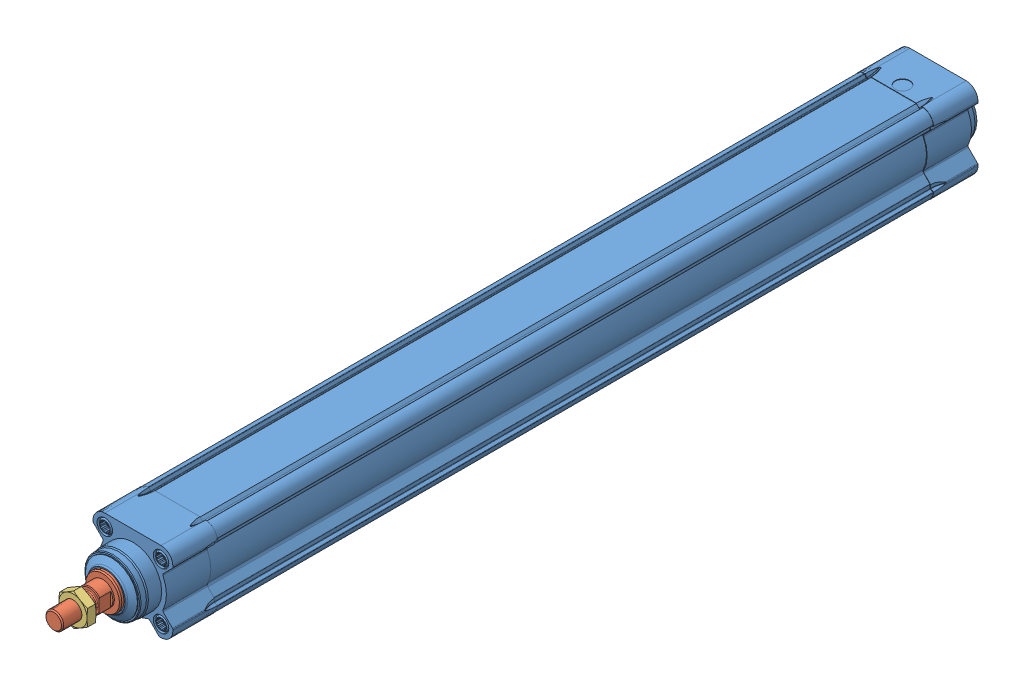
SolidWorks assembly Assem1, configuration Default. Lengths in mm.
Overall size (54 54 615.9).
5 component instances, 5 part files, 12 mates.
Components (placement in the parent):
- ESBF-BS-40-400---(ZR_-_-)-1: ESBF-BS-40-400---(ZR_-_-) [Default] at origin size (54 54 569)
- ESBF-BS-40-400-5P---(KS_0)-1: ESBF-BS-40-400-5P---(KS_0) [Default] at origin size (40 40 567.5)
- DIN-439-B - M12x1_25(F)-1: DIN-439-B - M12x1_25(F) [Default] at (0 0 40.5) x (1 0 0) z (0 -1 0) size (19 6 21.94)
- 717739 GUK M10x0_75-1: 717739 GUK M10x0_75 [Default] at (0 0 -540.8) x (0 1 0) z (0 0 -1) size (17.75 17.75 7.6)
- ESBF-BS-40-ESBF-BS-40---(KSA)-1: ESBF-BS-40-ESBF-BS-40---(KSA) [Default] at (0 0 -514) size (10 10 48.4)
Mates (geometry in assembly coordinates):
- LimitDistance1: limit distance = 0 mm anti-aligned: plane of ESBF-BS-40-400---(ZR_-_-)-1 through (0 0 -514) normal (0 0 1); plane of ESBF-BS-40-400-5P---(KS_0)-1 through (0 0 -514) normal (0 0 -1)
- Coincident1: coincident anti-aligned: line of ESBF-BS-40-400---(ZR_-_-)-1 through (0 0 80.9) axis (0 0 -1); line of ESBF-BS-40-400-5P---(KS_0)-1 through (0 0 -80.9) axis (0 0 1)
- Angle3: planar angle = 0 rad aligned: plane of ESBF-BS-40-400-5P---(KS_0)-1 through (0 0 0) normal (1 0 0); plane of ESBF-BS-40-400---(ZR_-_-)-1 through (0 0 0) normal (1 0 0)
- Distance1: distance = 0 mm anti-aligned: plane of ESBF-BS-40-400-5P---(KS_0)-1 through (0 0 37.5) normal (0 0 -1); plane of DIN-439-B - M12x1_25(F)-1 through (0 0 37.5) normal (0 0 1)
- Coincident2: coincident anti-aligned: line of ESBF-BS-40-400-5P---(KS_0)-1 through (0 0 -80.9) axis (0 0 1); line of DIN-439-B - M12x1_25(F)-1 through (0 0 90.5) axis (0 0 -1)
- Angle6: planar angle = 0 rad aligned: plane of DIN-439-B - M12x1_25(F)-1 through (0 0 40.5) normal (1 0 0); plane of ESBF-BS-40-400-5P---(KS_0)-1 through (0 0 0) normal (1 0 0)
- Distance2: distance = 0 mm anti-aligned: plane of ESBF-BS-40-400---(ZR_-_-)-1 through (0 0 -540.8) normal (0 0 1); plane of 717739 GUK M10x0_75-1 through (0 0 -540.8) normal (0 0 -1)
- Coincident3: coincident anti-aligned: line of ESBF-BS-40-400---(ZR_-_-)-1 through (0 0 50) axis (0 0 -1); line of 717739 GUK M10x0_75-1 through (0 0 -621.7) axis (0 0 1)
- Angle9: planar angle = 0 rad aligned: plane of 717739 GUK M10x0_75-1 through (0 0 -540.8) normal (0 1 0); plane of ESBF-BS-40-400---(ZR_-_-)-1 through (0 0 0) normal (0 1 0)
- Distance3: distance = 0 mm anti-aligned: plane of ESBF-BS-40-400---(ZR_-_-)-1 through (0 0 -514) normal (0 0 -1); plane of ESBF-BS-40-ESBF-BS-40---(KSA)-1 through (0 0 -514) normal (0 0 1)
- Coincident4: coincident anti-aligned: line of ESBF-BS-40-400---(ZR_-_-)-1 through (0 0 -80.9) axis (0 0 1); line of ESBF-BS-40-ESBF-BS-40---(KSA)-1 through (0 0 -433.1) axis (0 0 -1)
- Angle12: planar angle = 0 rad aligned: plane of ESBF-BS-40-ESBF-BS-40---(KSA)-1 through (0 0 -514) normal (1 0 0); plane of ESBF-BS-40-400---(ZR_-_-)-1 through (0 0 0) normal (1 0 0)
